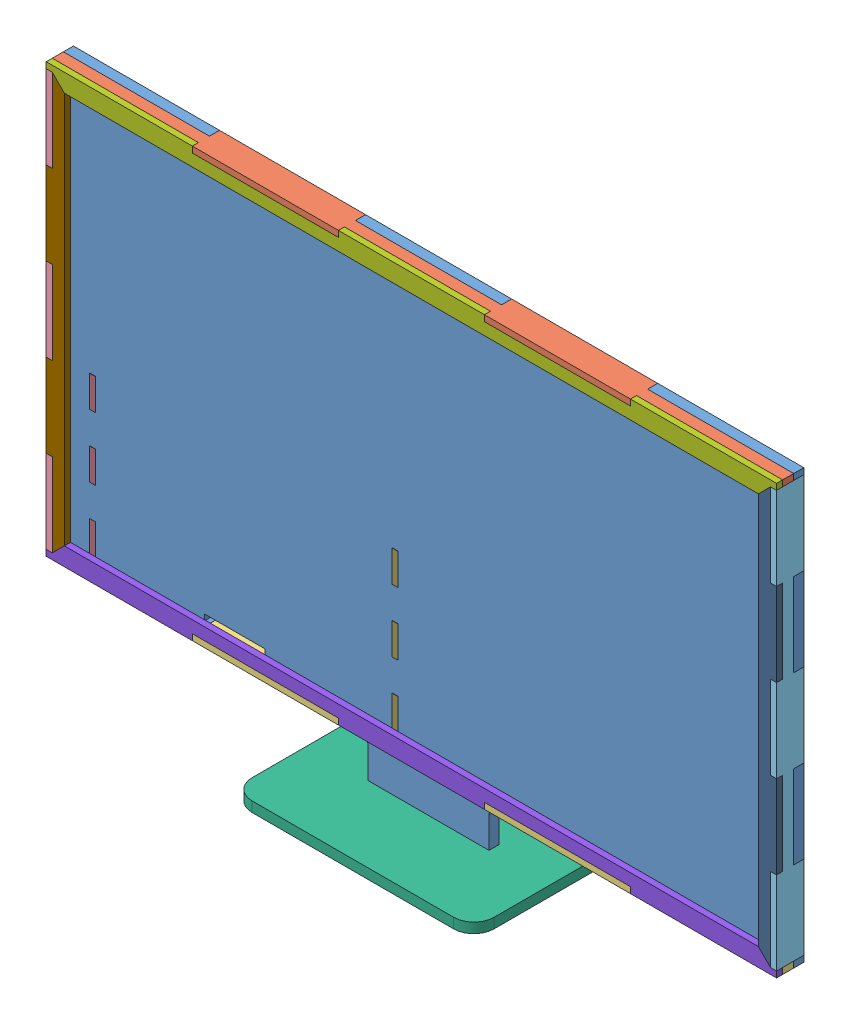
SolidWorks assembly Assem, configuration Default. Lengths in mm.
Overall size (362.3 242.5 80).
16 component instances, 15 part files, 30 mates.
Components (placement in the parent):
- A_1-1: A_1 [Default] at (136.8213 208.6918 288.3176) x (1 0 0) z (0 -1 0) size (362.3 5 242.5)
- B_1-3: B_1 [Default] at (136.8213 311.9418 295.0676) size (362.3 3 13.5)
- C_1-1: C_1 [Default] at (136.8213 102.4418 295.0676) size (362.3 3 13.5)
- D_1-1: D_1 [Default] at (-41.3287 208.6918 295.0676) x (0 1 0) z (0 0 1) size (206.5 3 13.5)
- F_1-2: F_1 [Default] at (317.9713 208.6918 295.0676) x (0 1 0) z (0 0 1) size (206.5 3 13.5)
- BASE-1: BASE [Default] at (136.8213 72.4415 290.8176) size (120 5 80)
- G_1-1: G_1 [Default] at (136.8213 310.8629 298.8176) x (1 0 0) z (0 -1 0) size (362.3 3 9)
- H_1-1: H_1 [Default] at (136.8213 106.5207 301.8176) x (1 0 0) z (0 1 0) size (362.3 3 9)
- I_1-1: I_1 [Default] at (-39.8287 208.6918 298.8176) x (0 1 0) z (1 0 0) size (206.5 3 9)
- J_1-1: J_1 [Default] at (313.4713 208.6918 298.8176) x (0 -1 0) z (-1 0 0) size (206.5 3 9)
- BoxAssembly-1: BoxAssembly [Default] at (96.8431 264.5841 361.7538) x (-1 0 0) z (0 -1 0) size (153 28 78)
  - BOX_A_1-1: BOX_A_1 [Default] at (51.6718 78.4362 117.2479) size (153 3 78)
  - BOX_B_1-1: BOX_B_1 [Default] at (-21.8282 78.4362 120.2479) x (0 0 -1) z (0 1 0) size (78 3 28)
  - BOX_C_1-1: BOX_C_1 [Default] at (128.1718 78.4362 120.2479) x (0 0 -1) z (0 1 0) size (78 3 28)
  - BOX_D_1-1: BOX_D_1 [Default] at (51.6718 80.9362 84.2479) x (1 0 0) z (0 1 0) size (147 3 23)
  - BOX_E_1-2: BOX_E_1 [Default] at (51.6718 93.4362 117.2479) size (153 3 78)
Mates (geometry in assembly coordinates):
- Coincident7: coincident aligned: plane of A_1-1 through (173.0513 314.9418 293.3176) normal (0 1 0); plane of B_1-3 through (136.8213 314.9418 295.0676) normal (0 1 0)
- Coincident9: coincident aligned: plane of A_1-1 through (96.8213 92.4418 288.3176) normal (0 0 -1); plane of B_1-3 through (28.1313 314.9418 288.3176) normal (0 0 -1)
- Coincident10: coincident anti-aligned: plane of A_1-1 through (28.1313 311.9415 293.3176) normal (1 0 0); plane of B_1-3 through (28.1313 314.9418 288.3176) normal (-1 0 0)
- Coincident11: coincident aligned: plane of A_1-1 through (245.5113 102.4418 293.3176) normal (0 -1 0); plane of C_1-1 through (136.8213 102.4418 295.0676) normal (0 -1 0)
- Coincident12: coincident anti-aligned: plane of A_1-1 through (245.5113 105.4421 293.3176) normal (-1 0 0); plane of C_1-1 through (245.5113 105.4418 288.3176) normal (1 0 0)
- Coincident13: coincident aligned: plane of A_1-1 through (96.8213 92.4418 288.3176) normal (0 0 -1); plane of C_1-1 through (173.0513 105.4418 288.3176) normal (0 0 -1)
- Coincident14: coincident aligned: plane of A_1-1 through (-44.3287 229.3418 293.3176) normal (-1 0 0); plane of D_1-1 through (-44.3287 208.6918 295.0676) normal (-1 0 0)
- Coincident15: coincident anti-aligned: plane of A_1-1 through (-41.3287 270.6418 293.3176) normal (0 1 0); plane of D_1-1 through (-44.3287 270.6418 288.3176) normal (0 -1 0)
- Coincident16: coincident aligned: plane of A_1-1 through (96.8213 92.4418 288.3176) normal (0 0 -1); plane of D_1-1 through (-44.3287 270.6418 288.3176) normal (0 0 -1)
- Coincident17: coincident aligned: plane of A_1-1 through (317.9713 229.3418 293.3176) normal (1 0 0); plane of F_1-2 through (317.9713 208.6918 295.0676) normal (1 0 0)
- Coincident18: coincident anti-aligned: plane of A_1-1 through (314.9713 270.6418 293.3176) normal (0 1 0); plane of F_1-2 through (314.9713 270.6418 288.3176) normal (0 -1 0)
- Coincident19: coincident aligned: plane of A_1-1 through (96.8213 92.4418 288.3176) normal (0 0 -1); plane of F_1-2 through (314.9713 270.6418 288.3176) normal (0 0 -1)
- Coincident22: coincident anti-aligned: plane of A_1-1 through (166.8213 72.4415 293.3176) normal (1 0 0); plane of BASE-1 through (166.8213 77.4415 288.3176) normal (-1 0 0)
- Coincident23: coincident anti-aligned: plane of A_1-1 through (96.8213 92.4418 288.3176) normal (0 0 -1); plane of BASE-1 through (154.8213 77.4415 288.3176) normal (0 0 1)
- Coincident24: coincident aligned: plane of A_1-1 through (130.8213 72.4415 293.3176) normal (0 -1 0); plane of BASE-1 through (186.8213 72.4415 260.8176) normal (0 -1 0)
- Coincident26: coincident aligned: plane of B_1-3 through (28.1313 314.9418 301.8176) normal (0 0 1); plane of G_1-1 through (136.8213 310.8629 301.8176) normal (0 0 1)
- Coincident27: coincident aligned: plane of B_1-3 through (-44.3287 314.9418 293.3176) normal (-1 0 0); plane of G_1-1 through (-44.3287 314.9418 301.8176) normal (-1 0 0)
- Coincident28: coincident aligned: plane of B_1-3 through (136.8213 314.9418 295.0676) normal (0 1 0); plane of G_1-1 through (-44.3287 314.9418 301.8176) normal (0 1 0)
- Coincident30: coincident aligned: plane of C_1-1 through (-44.3287 105.4418 293.3176) normal (-1 0 0); plane of H_1-1 through (-44.3287 102.4418 298.8176) normal (-1 0 0)
- Coincident31: coincident aligned: plane of D_1-1 through (-44.3287 105.4418 301.8176) normal (0 0 1); plane of H_1-1 through (136.8213 106.5207 301.8176) normal (0 0 1)
- Coincident32: coincident aligned: plane of C_1-1 through (136.8213 102.4418 295.0676) normal (0 -1 0); plane of H_1-1 through (-44.3287 102.4418 298.8176) normal (0 -1 0)
- Coincident34: coincident aligned: plane of D_1-1 through (-44.3287 188.0418 301.8176) normal (0 0 1); plane of I_1-1 through (-39.8287 208.6918 301.8176) normal (0 0 1)
- Coincident35: coincident anti-aligned: plane of D_1-1 through (-44.3287 270.6418 298.8176) normal (0 -1 0); plane of I_1-1 through (-44.3287 270.6418 301.8176) normal (0 1 0)
- Coincident36: coincident aligned: plane of D_1-1 through (-44.3287 208.6918 295.0676) normal (-1 0 0); plane of I_1-1 through (-44.3287 229.3418 301.8176) normal (-1 0 0)
- Coincident37: coincident aligned: plane of F_1-2 through (314.9713 188.0418 301.8176) normal (0 0 1); plane of J_1-1 through (313.4713 208.6918 301.8176) normal (0 0 1)
- Coincident38: coincident: moEndPointRef_w of F_1-2; plane of J_1-1 through (317.9713 270.6418 301.8176) normal (0 1 0)
- Coincident39: coincident aligned: plane of F_1-2 through (317.9713 208.6918 295.0676) normal (1 0 0); plane of J_1-1 through (317.9713 270.6418 301.8176) normal (1 0 0)
- Coincident40: coincident anti-aligned: plane of A_1-1 through (-31.3287 167.877 293.3176) normal (1 0 0); plane of BoxAssembly-1/BOX_C_1-1 through (-31.3287 144.3362 283.3176) normal (-1 0 0)
- Coincident41: coincident anti-aligned: plane of A_1-1 through (96.8213 92.4418 288.3176) normal (0 0 -1); plane of BoxAssembly-1/BOX_C_1-1 through (-28.3287 152.1362 288.3176) normal (0 0 1)
- Coincident42: coincident anti-aligned: plane of A_1-1 through (-28.3287 105.3362 293.3176) normal (0 1 0); plane of BoxAssembly-1/BOX_C_1-1 through (-28.3287 105.3362 293.3176) normal (0 -1 0)
